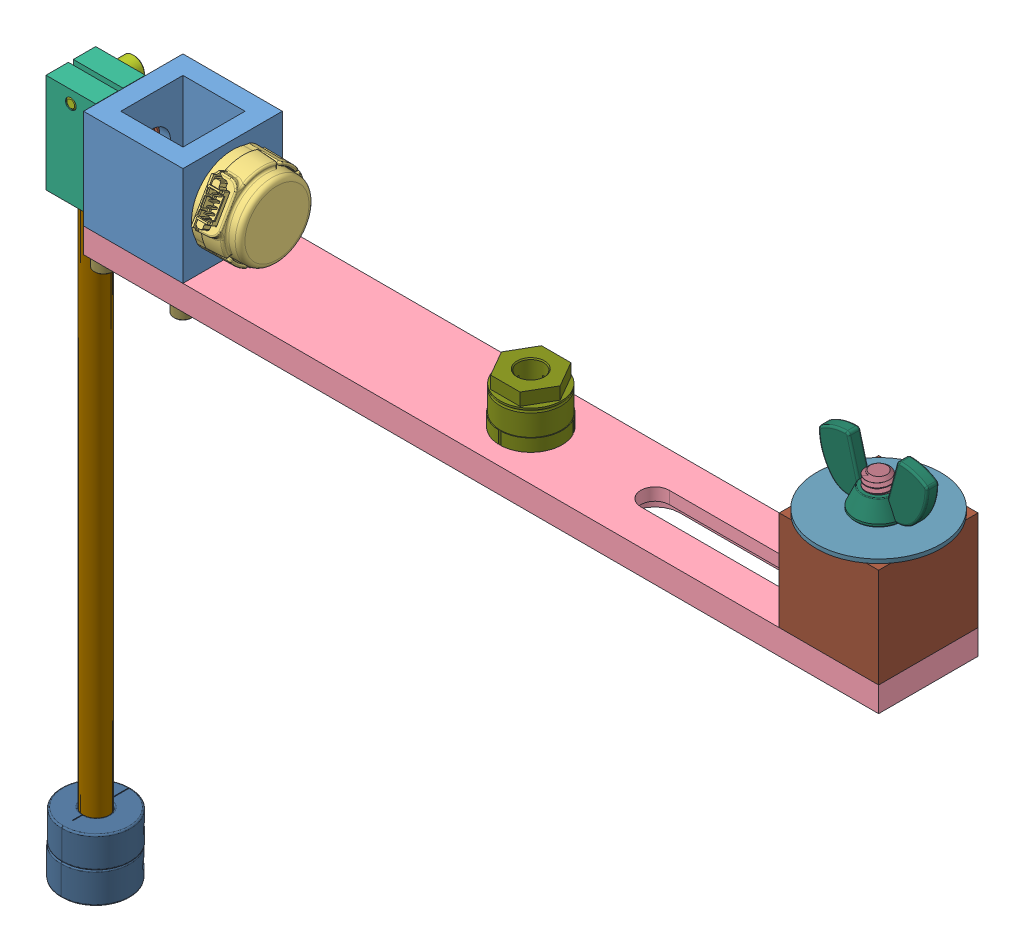
SolidWorks assembly CompleteArm, configuration Default. Lengths in mm.
Overall size (227.42 196.69 31.96).
23 component instances, 16 part files, 25 mates.
Components (placement in the parent):
- EncoderBlock-1: EncoderBlock [Default] at (-66.0559 16.3168 69.5231) size (37.74 31.82 30.88)
  - BearingBlock-1: BearingBlock [Default] at (-16.3048 -10.4057 15.6733) size (25.4 25.4 25.4)
  - BallBearing-1: BallBearing [57155K322] at (-15.7333 2.2943 2.9733) x (0 0 -1) z (1 0 0) size (10.72 10.72 3.17)
  - BallBearing-2: BallBearing [57155K322] at (4.9042 2.2943 2.9733) x (0 0 -1) z (1 0 0) size (10.72 10.72 3.17)
  - E4P-X-250-X-S-D-D-X-1: E4P-X-250-X-S-D-D-X [Default] at (9.0952 2.2943 2.9733) x (0 -0.866025 -0.5) z (0 -0.5 0.866025) size (24.23 14.38 21.67)
- HorizontalArm-2: HorizontalArm [Default] at (-82.3607 5.9112 59.7963) x (1 0 0) z (0 0 -1) size (203.2 6.35 25.4)
- PendulumArm-1: PendulumArm [Default] at (-72.4176 15.2319 73.9429) x (0 -1 -0.000196) z (0 0.000196 -1) size (178.79 55.9 18.78)
  - EncoderShaft-1: EncoderShaft [Default] at (-3.379 -24.9057 1.4472) size (6.35 50.8 6.35)
  - Clamp-1: Clamp [Default] at (12.4973 13.1943 7.7941) x (0 1 0) z (0.000196 0 1) size (12.7 25.4 12.7)
  - 6_32CapScrew-1: 6_32CapScrew [90128A148] at (-9.7302 19.5443 -4.9016) x (-0.923728 -0.383049 0.000181) z (-0.000196 0 -1) size (5.74 5.74 16.56)
  - 10_32SetScrew-1: 10_32SetScrew [90289A344] at (12.5677 19.5443 1.4441) x (-0.000016 0.996648 -0.081814) z (1 0 -0.000196) size (4.88 4.93 16.29)
  - QuarterInchThreadedRod-1: QuarterInchThreadedRod [6516K51] at (88.696 19.5443 1.4291) x (1 0 -0.000196) z (0 1 0) size (153.23 6.35 6.35)
  - ShaftCollar-1: ShaftCollar [6435K12] at (160.9273 19.6316 1.415) x (-0.000196 0 -1) z (1 0 -0.000196) size (17.46 17.64 7.94)
  - ShaftCollar-2: ShaftCollar [6435K12] at (152.9898 19.457 1.4165) x (-0.000196 0 -1) z (1 0 -0.000196) size (17.46 17.64 7.94)
- CounterWeight-1: CounterWeight [Default] at (95.4393 5.9112 85.1963) size (25.4 25.4 25.4)
- 4_40CapScrew-1: 4_40CapScrew [90128A110] at (-79.8207 12.2612 82.6563) x (1 0 0) z (0 1 0) size (4.65 4.65 15.82)
- 4_40CapScrew-4: 4_40CapScrew [90128A110] at (-59.5007 12.2612 62.3363) x (1 0 0) z (0 1 0) size (4.65 4.65 15.82)
- 4_40CapScrew-5: 4_40CapScrew [90128A110] at (-79.8207 12.2612 62.3363) x (1 0 0) z (0 1 0) size (4.65 4.65 15.82)
- 4_40CapScrew-6: 4_40CapScrew [90128A110] at (-59.5007 12.2612 82.6563) x (1 0 0) z (0 1 0) size (4.65 4.65 15.82)
- 1_4x20CapScrew-1: 1_4x20CapScrew [93615A425] at (108.1393 40.8362 72.4963) x (1 0 0) z (0 1 0) size (9.53 9.53 42.04)
- LargeWasher-1: LargeWasher [91525A124] at (108.1393 31.3112 72.4963) x (1 0 0) z (0 -1 0) size (31.75 31.75 1.02)
- WingNut-1: WingNut [93575A029] at (108.1393 32.3272 72.4963) x (1 0 0) z (0 -1 0) size (27.78 12.25 14.47)
- Keyless Bushing_withFeatures-1: Keyless Bushing_withFeatures [Default] at (19.2393 -0.3118 72.4963) x (1 0 0) z (0 -1 0) size (16 16 19.18)
Mates (geometry in assembly coordinates):
- Concentric1: concentric aligned: circle of EncoderBlock-1/BearingBlock-1; circle of HorizontalArm-2
- Concentric2: concentric aligned: circle of EncoderBlock-1/BearingBlock-1; circle of HorizontalArm-2
- Coincident1: coincident anti-aligned: plane of EncoderBlock-1/BearingBlock-1 through (-82.3607 5.9112 85.1963) normal (0 -1 0); plane of HorizontalArm-2 through (-82.3607 5.9112 59.7963) normal (0 1 0)
- Concentric3: concentric aligned: circle of EncoderBlock-1/BallBearing-1; circle of PendulumArm-1/EncoderShaft-1
- Parallel1: parallel aligned: plane of EncoderBlock-1/BearingBlock-1 through (-82.3607 31.3112 85.1963) normal (0 1 0); plane of PendulumArm-1/Clamp-1 through (-85.6119 28.1362 66.1463) normal (0 1 0)
- Distance1: distance = 3.2512 mm anti-aligned: plane of EncoderBlock-1/BearingBlock-1 through (-82.3607 31.3112 85.1963) normal (-1 0 0); plane of PendulumArm-1/Clamp-1 through (-85.6119 28.1362 66.1463) normal (1 0 0)
- Coincident4: coincident anti-aligned: plane of HorizontalArm-2 through (-82.3607 5.9112 59.7963) normal (0 1 0); plane of CounterWeight-1 through (95.4393 5.9112 85.1963) normal (0 -1 0)
- Coincident5: coincident anti-aligned: line of HorizontalArm-2 through (120.8393 5.9112 85.1963) axis (-1 0 0); line of CounterWeight-1 through (95.4393 5.9112 85.1963) axis (1 0 0)
- Coincident6: coincident anti-aligned: line of HorizontalArm-2 through (120.8393 5.9112 59.7963) axis (0 0 1); line of CounterWeight-1 through (120.8393 5.9112 85.1963) axis (0 0 -1)
- Concentric4: concentric anti-aligned: circle of HorizontalArm-2; circle of 4_40CapScrew-1
- Coincident7: coincident anti-aligned: plane of HorizontalArm-2 through (-82.3607 -0.4388 59.7963) normal (0 -1 0); plane of 4_40CapScrew-1 through (-79.8207 -0.4388 82.6563) normal (0 1 0)
- Concentric5: concentric anti-aligned: circle of HorizontalArm-2; circle of 4_40CapScrew-4
- Coincident8: coincident anti-aligned: plane of HorizontalArm-2 through (-82.3607 -0.4388 59.7963) normal (0 -1 0); plane of 4_40CapScrew-4 through (-59.5007 -0.4388 62.3363) normal (0 1 0)
- Concentric6: concentric anti-aligned: circle of HorizontalArm-2; circle of 4_40CapScrew-5
- Coincident9: coincident anti-aligned: plane of HorizontalArm-2 through (-82.3607 -0.4388 59.7963) normal (0 -1 0); plane of 4_40CapScrew-5 through (-79.8207 -0.4388 62.3363) normal (0 1 0)
- Concentric7: concentric anti-aligned: circle of HorizontalArm-2; circle of 4_40CapScrew-6
- Coincident10: coincident anti-aligned: plane of HorizontalArm-2 through (-82.3607 -0.4388 59.7963) normal (0 -1 0); plane of 4_40CapScrew-6 through (-59.5007 -0.4388 82.6563) normal (0 1 0)
- Concentric8: concentric aligned: circle of HorizontalArm-2; circle of 1_4x20CapScrew-1
- Coincident11: coincident anti-aligned: plane of HorizontalArm-2 through (108.1393 2.7362 72.4963) normal (0 -1 0); plane of 1_4x20CapScrew-1 through (108.1393 2.7362 72.4963) normal (0 1 0)
- Concentric9: concentric anti-aligned: circle of 1_4x20CapScrew-1; circle of LargeWasher-1
- Coincident12: coincident anti-aligned: plane of CounterWeight-1 through (95.4393 31.3112 85.1963) normal (0 1 0); plane of LargeWasher-1 through (108.1393 31.3112 72.4963) normal (0 -1 0)
- Concentric10: concentric aligned: circle of LargeWasher-1; circle of WingNut-1
- Coincident13: coincident anti-aligned: plane of LargeWasher-1 through (108.1393 32.3272 72.4963) normal (0 1 0); plane of WingNut-1 through (108.1393 32.3272 72.4963) normal (0 -1 0)
- Concentric11: concentric anti-aligned: circle of HorizontalArm-2; circle of Keyless Bushing_withFeatures-1
- Coincident15: coincident aligned: plane of HorizontalArm-2 through (-82.3607 -0.4388 59.7963) normal (0 -1 0); plane of Keyless Bushing_withFeatures-1 through (19.2393 -0.4388 72.4963) normal (0 -1 0)
